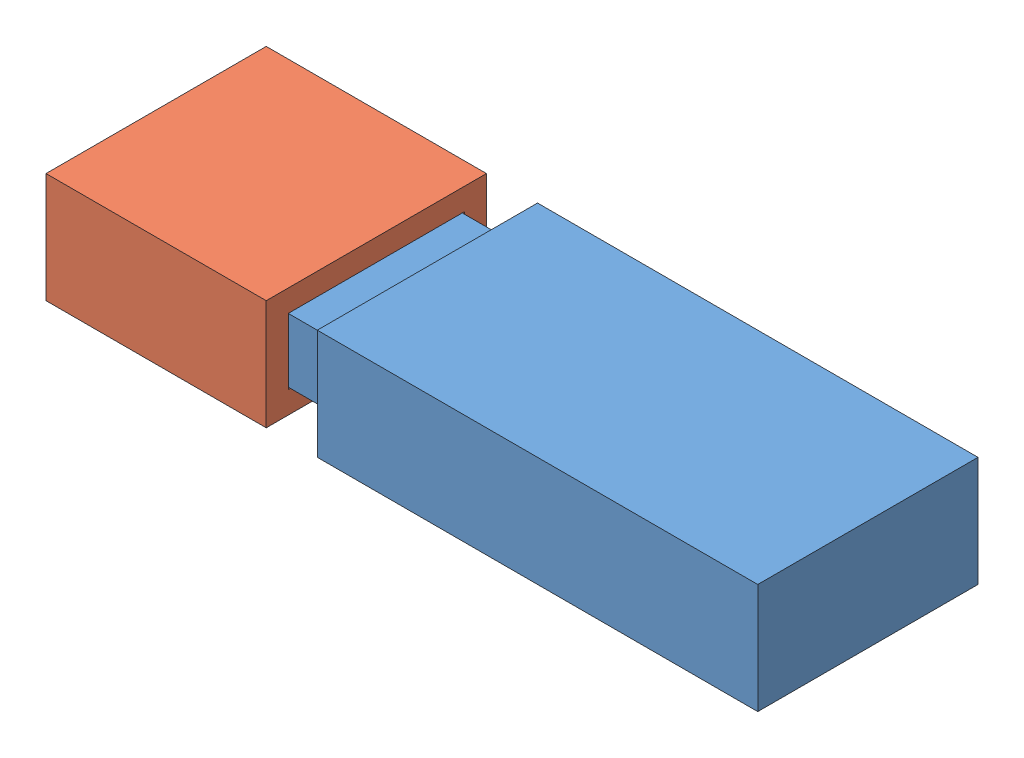
SolidWorks assembly 装配体1, configuration 默认. Lengths in mm.
Overall size (129.47 20.2 40.2).
2 component instances, 2 part files, 3 mates.
Components (placement in the parent):
- flash_body-1: flash_body [默认] at (-53.9189 -80.568 95.7041) size (100 20 40)
- flash_hat-1: flash_hat [默认] at (-43.3916 -60.768 95.5041) x (-1 0 0) z (0 0 1) size (40 20 40)
Mates (geometry in assembly coordinates):
- 重合16: coincident anti-aligned: plane of flash_body-1 through (-33.9189 -64.768 95.7041) normal (0 1 0); plane of flash_hat-1 through (-63.3916 -64.768 95.5041) normal (0 -1 0)
- 重合18: coincident anti-aligned: plane of flash_hat-1 through (-63.3916 -60.768 91.5041) normal (0 0 -1); plane of flash_body-1 through (-33.9189 -80.568 91.5041) normal (0 0 1)
- 平行7: parallel aligned: plane of flash_hat-1 through (-43.3916 -80.768 95.5041) normal (0 0 1); line of flash_body-1 through (-33.9189 -60.568 95.7041) axis (1 0 0)
